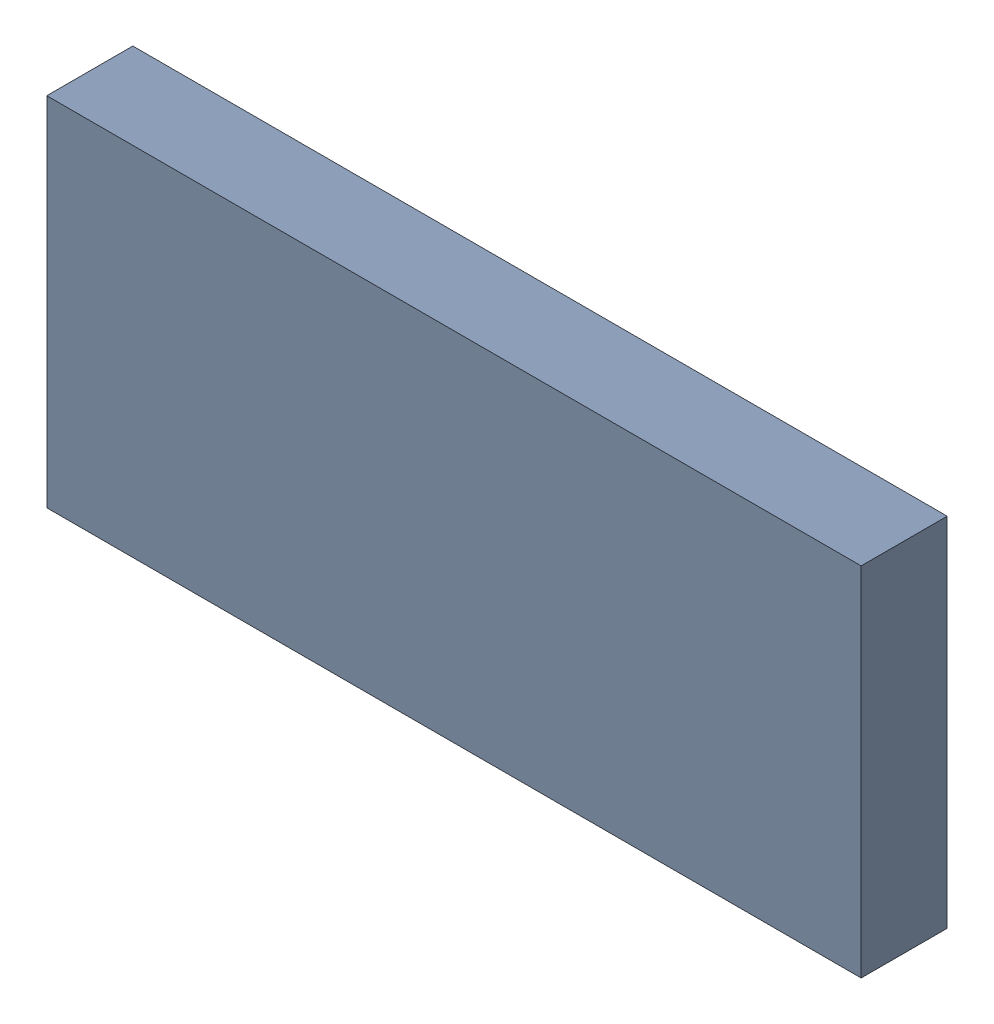
SolidWorks assembly 6327400000, configuration Default. Lengths in mm.
Overall size (2.4 1.05 0.25).
2 component instances, 1 part files, 0 mates.
Components (placement in the parent):
- 6701982208-1:  [Default] at (27.7 14.8 0) (suppressed, hidden)
- Extruded-12-1: Extruded-12 [Default] at origin size (2.4 1.05 0.25)
